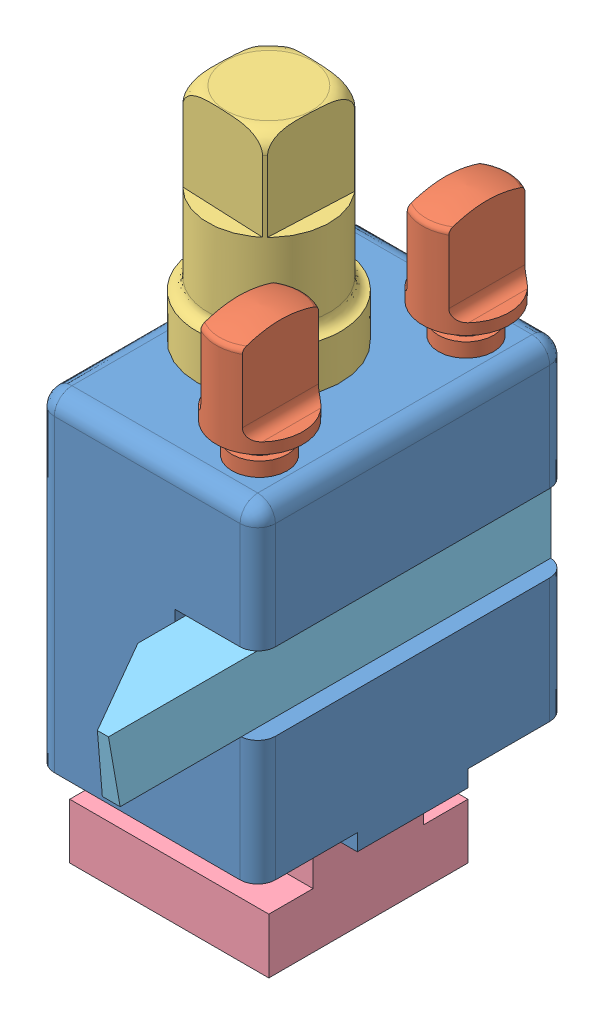
SolidWorks assembly Sub_Assembly_Tool_Post, configuration RHS. Lengths in mm.
Overall size (34.92 97.21 63.5).
6 component instances, 5 part files, 10 mates.
Components (placement in the parent):
- Tool_Post-1: Tool_Post [Default] at (19.3679 28.1926 36.3512) size (31.75 49.21 44.45)
- Set_Screw-3: Set_Screw [Default] at (28.0991 32.209 51.1678) size (12.45 38.14 12.45)
- Set_Screw-4: Set_Screw [Default] at (28.0991 32.209 21.5345) size (12.45 38.14 12.45)
- Bolt-2: Bolt [Default] at (14.6054 -8.7168 36.3512) x (-0.044067 0 0.999029) z (-0.999029 0 -0.044067) size (20.64 92.64 20.64)
- Tool_Block_Nut-2: Tool_Block_Nut [Default] at (14.6054 -13.2888 36.3512) size (28.57 11.91 28.57)
- Cutter-1: Cutter [Default] at (23.3366 22.6363 14.1262) x (-1 0 0) z (0 0 -1) size (9.53 9.53 63.5)
Mates (geometry in assembly coordinates):
- ProfileCenter1: profile center = 2.032 mm anti-aligned: circle of Set_Screw-3; circle of Tool_Post-1
- ProfileCenter2: profile center = 2.032 mm anti-aligned: circle of Set_Screw-4; circle of Tool_Post-1
- ProfileCenter3: profile center = 0 mm aligned: circle of Bolt-2; circle of Tool_Post-1
- ProfileCenter4: profile center = 4.572 mm anti-aligned: circle of Tool_Block_Nut-2; circle of Bolt-2
- Coincident1: coincident: plane of Tool_Post-1 through (19.3679 28.1926 58.5762) normal (0 0 1); plane of Cutter-1
- Coincident2: coincident: plane of Tool_Post-1 through (35.2429 22.6363 58.5762) normal (0 1 0); plane of Cutter-1
- Coincident3: coincident anti-aligned: plane of Tool_Post-1 through (23.3366 33.7488 58.5762) normal (1 0 0); plane of Cutter-1
- Coincident4: coincident: plane of Tool_Post-1 through (35.2429 22.6363 58.5762) normal (0 1 0); plane of Cutter-1 through (23.3366 22.6363 14.1262) normal (0 -1 0)
- Coincident5: coincident: plane of Tool_Post-1 through (19.3679 28.1926 14.1262) normal (0 0 -1); plane of Cutter-1 through (32.8616 32.1613 14.1262) normal (0 0 -1)
- Coincident6: coincident anti-aligned: plane of Tool_Post-1 through (23.3366 33.7488 58.5762) normal (1 0 0); plane of Cutter-1 through (23.3366 32.1613 14.1262) normal (-1 0 0)
